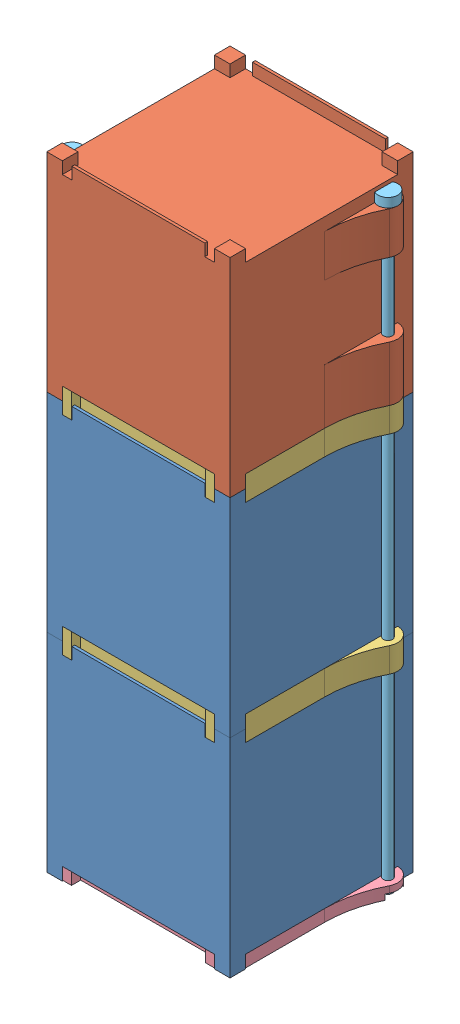
SolidWorks assembly MADS Mockup V1, configuration Default. Lengths in mm.
Overall size (115.58 340.5 100).
8 component instances, 5 part files, 0 mates.
Components (placement in the parent):
- Standard CubeSat-1: Standard CubeSat [Default] at (0 46.5 0) size (100 113.5 100)
- MADS Hat-1: MADS Hat [Default] at origin size (115.58 113.5 100)
- Standard CubeSat-2: Standard CubeSat [Default] at (0 -67 0) size (100 113.5 100)
- Standard Spacer-1: Standard Spacer [Default] at origin size (115.58 13.5 100)
- Keeper Plate-1: Keeper Plate [Default] at (0 83 0) size (115.58 6.5 100)
- Standard Spacer-2: Standard Spacer [Default] at (0 -113.5 0) size (115.58 13.5 100)
- Guide Rod-1: Guide Rod [Default] at origin size (7.79 331.5 10.82)
- Guide Rod-2: Guide Rod [Default] at (42.1562 0 -64.5778) x (-1 0 0) z (0 0 -1) size (7.79 331.5 10.82)
